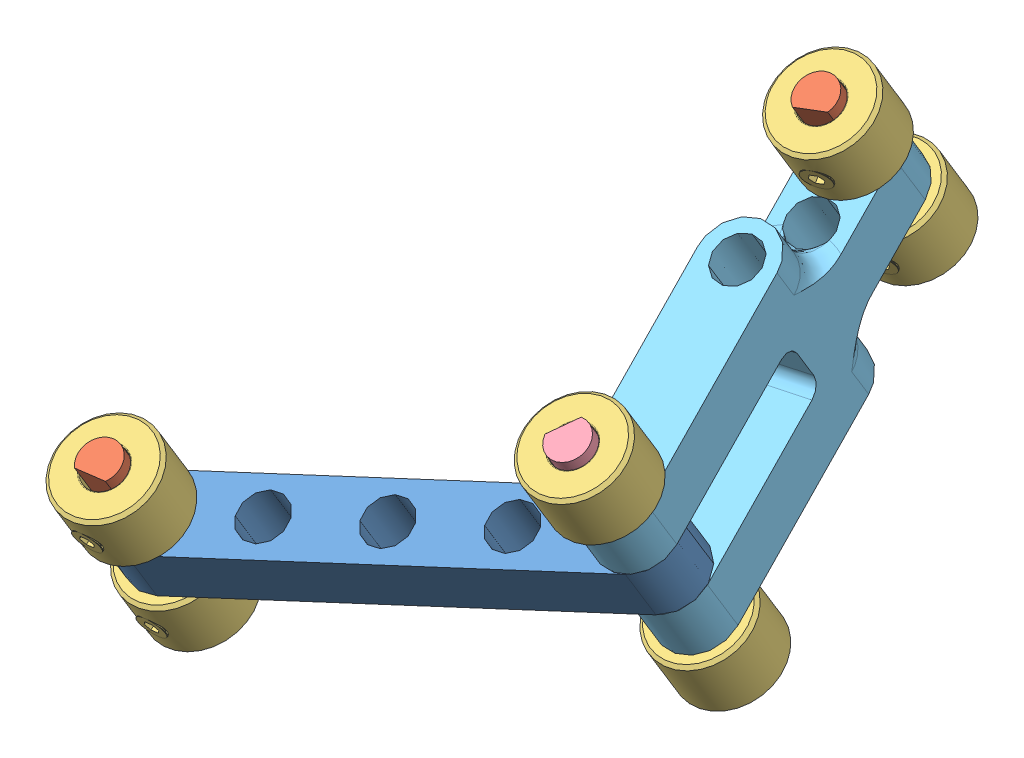
SolidWorks assembly Link Assembly, configuration Default. Lengths in mm.
Overall size (35.74 36.26 46.82).
11 component instances, 5 part files, 31 mates.
Components (placement in the parent):
- Base Link-1: Base Link [Default] at (197.5277 -2.253 -4.4836) x (0.901914 0.22428 -0.369121) z (0 0.854612 0.519267) size (35.35 5.35 4.5)
- Aluminum D Shaft-1: Aluminum D Shaft [Default] at (183.999 -5.6172 1.0532) x (0 -0.854612 -0.519267) z (-0.995127 -0.051201 0.084268) size (16 2.4 2.9)
- 6056N11_Carbon Steel Set Screw Collar-1: 6056N11_Carbon Steel Set Screw Collar [6056N11] at (183.999 -11.8131 -2.7114) x (-0.995127 -0.051201 0.084268) z (0 0.854612 0.519267) size (7 7.1 5)
- 6056N11_Carbon Steel Set Screw Collar-2: 6056N11_Carbon Steel Set Screw Collar [6056N11] at (183.999 -3.6943 2.2216) x (-0.995127 -0.051201 0.084268) z (0 0.854612 0.519267) size (7 7.1 5)
- Aluminum D Shaft-2: Aluminum D Shaft [Default] at (206.6692 13.8914 -31.0541) x (0 0.854612 0.519267) z (0.941762 0.17462 -0.28739) size (16 2.4 2.9)
- 6056N11_Carbon Steel Set Screw Collar-3: 6056N11_Carbon Steel Set Screw Collar [6056N11] at (206.6692 7.6955 -34.8188) x (-0.941762 -0.17462 0.28739) z (0 0.854612 0.519267) size (7 7.1 5)
- 6056N11_Carbon Steel Set Screw Collar-4: 6056N11_Carbon Steel Set Screw Collar [6056N11] at (206.6692 15.8143 -29.8858) x (-0.941762 -0.17462 0.28739) z (0 0.854612 0.519267) size (7 7.1 5)
- Link D Shaft-1: Link D Shaft [Default] at (211.0564 1.1112 -10.0204) x (0 -0.854612 -0.519267) z (0.552359 0.432864 -0.71241) size (25 2.4 2.9)
- 6056N11_Carbon Steel Set Screw Collar-5: 6056N11_Carbon Steel Set Screw Collar [6056N11] at (211.0564 -8.9305 -16.1218) x (0.552359 0.432864 -0.71241) z (0 0.854612 0.519267) size (7 7.1 5)
- 6056N11_Carbon Steel Set Screw Collar-6: 6056N11_Carbon Steel Set Screw Collar [6056N11] at (211.0564 6.8798 -6.5153) x (0.552359 0.432864 -0.71241) z (0 0.854612 0.519267) size (7 7.1 5)
- Upper Link-2: Upper Link [Default] at (209.3015 6.2233 -18.4339) x (-0.175488 0.511209 -0.84135) z (0 0.854612 0.519267) size (30.35 5.35 13.5)
Mates (geometry in assembly coordinates):
- Concentric30: concentric aligned: cylinder of Base Link-1 through (211.0564 3.0341 -8.852) axis (0 -0.854612 -0.519267) radius 1.675; cylinder of Upper Link-1 through (199.4791 31.9793 -36.1428) axis (0 -0.854612 -0.519267) radius 1.51
- Coincident32: coincident aligned: plane of Base Link-1 through (197.5277 -2.253 -4.4836) normal (0 0.854612 0.519267); plane of Upper Link-1 through (206.0825 22.3111 -33.2299) normal (0 0.854612 0.519267)
- Concentric52: concentric aligned: cylinder of Aluminum D Shaft-1 through (183.999 1.2197 5.2074) axis (0 -0.854612 -0.519267) radius 1.45; cylinder of 6056N11_Carbon Steel Set Screw Collar-1 through (183.999 -7.5401 -0.1151) axis (0 -0.854612 -0.519267) radius 1.5
- Parallel22: parallel aligned: plane of Aluminum D Shaft-1 through (184.0927 0.7288 6.0153) normal (0.098603 -0.516737 0.850447); plane of 6056N11_Carbon Steel Set Screw Collar-1 through (184.3441 -11.4852 1.5633) normal (0.098603 -0.516737 0.850447)
- Concentric53: concentric aligned: cylinder of Aluminum D Shaft-1 through (183.999 1.2197 5.2074) axis (0 -0.854612 -0.519267) radius 1.45; cylinder of 6056N11_Carbon Steel Set Screw Collar-2 through (183.999 0.5787 4.8179) axis (0 -0.854612 -0.519267) radius 1.5
- Parallel23: parallel aligned: plane of Aluminum D Shaft-1 through (184.0927 0.7288 6.0153) normal (0.098603 -0.516737 0.850447); plane of 6056N11_Carbon Steel Set Screw Collar-2 through (184.3441 -3.3664 6.4963) normal (0.098603 -0.516737 0.850447)
- Coincident134: coincident aligned: plane of Base Link-1 through (197.5277 -2.253 -4.4836) normal (0 0.854612 0.519267); plane of Aluminum D Shaft-2 through (206.6692 13.8914 -31.0541) normal (0 0.854612 0.519267)
- Concentric78: concentric anti-aligned: cylinder of Aluminum D Shaft-2 through (206.6692 7.0545 -35.2083) axis (0 0.854612 0.519267) radius 1.45; cylinder of 6056N11_Carbon Steel Set Screw Collar-4 through (206.6692 20.0874 -27.2894) axis (0 -0.854612 -0.519267) radius 1.5
- Concentric79: concentric anti-aligned: cylinder of Aluminum D Shaft-2 through (206.6692 7.0545 -35.2083) axis (0 0.854612 0.519267) radius 1.45; cylinder of 6056N11_Carbon Steel Set Screw Collar-3 through (206.6692 11.9685 -32.2225) axis (0 -0.854612 -0.519267) radius 1.5
- Parallel31: parallel aligned: plane of Aluminum D Shaft-2 through (206.9887 6.59 -34.4437) normal (0.336281 -0.489026 0.804841); plane of 6056N11_Carbon Steel Set Screw Collar-3 through (207.8462 8.1204 -30.7037) normal (0.336281 -0.489026 0.804841)
- Parallel32: parallel aligned: plane of Aluminum D Shaft-2 through (206.9887 6.59 -34.4437) normal (0.336281 -0.489026 0.804841); plane of 6056N11_Carbon Steel Set Screw Collar-4 through (207.8462 16.2392 -25.7707) normal (0.336281 -0.489026 0.804841)
- Coincident178: coincident anti-aligned: plane of Upper Link-1 through (206.0825 22.3111 -33.2299) normal (0 0.854612 0.519267); plane of Link D Shaft-1 through (211.0564 1.1112 -10.0204) normal (0 -0.854612 -0.519267)
- Concentric113: concentric anti-aligned: cylinder of Upper Link-1 through (199.4791 20.4421 -43.1529) axis (0 0.854612 0.519267) radius 1.51; cylinder of Link D Shaft-1 through (211.0564 11.7938 -3.5295) axis (0 -0.854612 -0.519267) radius 1.45
- Concentric114: concentric aligned: cylinder of Link D Shaft-1 through (211.0564 11.7938 -3.5295) axis (0 -0.854612 -0.519267) radius 1.45; cylinder of 6056N11_Carbon Steel Set Screw Collar-5 through (211.0564 -4.6574 -13.5254) axis (0 -0.854612 -0.519267) radius 1.5
- Parallel33: parallel aligned: plane of Link D Shaft-1 through (210.2645 12.0663 -3.978) normal (-0.833606 0.286822 -0.472053); plane of 6056N11_Carbon Steel Set Screw Collar-5 through (208.1388 -5.7901 -16.4758) normal (-0.833606 0.286822 -0.472053)
- Concentric115: concentric aligned: cylinder of Link D Shaft-1 through (211.0564 11.7938 -3.5295) axis (0 -0.854612 -0.519267) radius 1.45; cylinder of 6056N11_Carbon Steel Set Screw Collar-6 through (211.0564 11.1529 -3.919) axis (0 -0.854612 -0.519267) radius 1.5
- Parallel34: parallel aligned: plane of Link D Shaft-1 through (210.2645 12.0663 -3.978) normal (-0.833606 0.286822 -0.472053); plane of 6056N11_Carbon Steel Set Screw Collar-6 through (208.1388 10.0202 -6.8693) normal (-0.833606 0.286822 -0.472053)
- Coincident179: coincident anti-aligned: plane of Upper Link-1 through (206.0825 16.5425 -36.735) normal (0 -0.854612 -0.519267); plane of 6056N11_Carbon Steel Set Screw Collar-5 through (211.0564 -4.6574 -13.5254) normal (0 0.854612 0.519267)
- Coincident181: coincident anti-aligned: plane of Upper Link-1 through (206.0825 28.0798 -29.7249) normal (0 0.854612 0.519267); plane of 6056N11_Carbon Steel Set Screw Collar-6 through (211.0564 6.8798 -6.5153) normal (0 -0.854612 -0.519267)
- Concentric130: concentric anti-aligned: cylinder of Link D Shaft-1 through (211.0564 11.7938 -3.5295) axis (0 -0.854612 -0.519267) radius 1.45; cylinder of Upper Link-2 through (211.0564 -4.6574 -13.5254) axis (0 0.854612 0.519267) radius 1.675
- Concentric131: concentric anti-aligned: cylinder of Aluminum D Shaft-2 through (206.6692 7.0545 -35.2083) axis (0 0.854612 0.519267) radius 1.45; cylinder of Upper Link-2 through (206.6692 15.8143 -29.8858) axis (0 -0.854612 -0.519267) radius 1.675
- Concentric132: concentric anti-aligned: cylinder of Base Link-1 through (211.0564 3.0341 -8.852) axis (0 -0.854612 -0.519267) radius 1.675; cylinder of Upper Link-2 through (211.0564 -4.6574 -13.5254) axis (0 0.854612 0.519267) radius 1.675
- Coincident204: coincident anti-aligned: plane of 6056N11_Carbon Steel Set Screw Collar-5 through (211.0564 -4.6574 -13.5254) normal (0 0.854612 0.519267); plane of Upper Link-2 through (208.4241 3.0107 -26.1457) normal (0 -0.854612 -0.519267)
- Coincident205: coincident anti-aligned: plane of 6056N11_Carbon Steel Set Screw Collar-6 through (211.0564 6.8798 -6.5153) normal (0 -0.854612 -0.519267); plane of Upper Link-2 through (208.4241 14.548 -19.1356) normal (0 0.854612 0.519267)
- Coincident206: coincident anti-aligned: plane of Link D Shaft-1 through (211.0564 1.1112 -10.0204) normal (0 -0.854612 -0.519267); plane of Upper Link-2 through (209.3015 6.2233 -18.4339) normal (0 0.854612 0.519267)
- Coincident207: coincident aligned: plane of Base Link-1 through (197.5277 -2.253 -4.4836) normal (0 0.854612 0.519267); plane of Upper Link-2 through (209.3015 6.2233 -18.4339) normal (0 0.854612 0.519267)
- Parallel35: parallel aligned: plane of Aluminum D Shaft-2 through (206.9887 6.59 -34.4437) normal (0.336281 -0.489026 0.804841); plane of 6056N11_Carbon Steel Set Screw Collar-4 through (207.8462 16.2392 -25.7707) normal (0.336281 -0.489026 0.804841)
- Parallel36: parallel aligned: plane of Aluminum D Shaft-2 through (206.9887 6.59 -34.4437) normal (0.336281 -0.489026 0.804841); plane of 6056N11_Carbon Steel Set Screw Collar-3 through (207.8462 8.1204 -30.7037) normal (0.336281 -0.489026 0.804841)
- Concentric133: concentric aligned: cylinder of Base Link-1 through (183.999 -3.6943 2.2216) axis (0 -0.854612 -0.519267) radius 1.675; cylinder of Aluminum D Shaft-1 through (183.999 1.2197 5.2074) axis (0 -0.854612 -0.519267) radius 1.45
- Coincident212: coincident anti-aligned: plane of Base Link-1 through (197.5277 -2.253 -4.4836) normal (0 0.854612 0.519267); plane of Aluminum D Shaft-1 through (183.999 -5.6172 1.0532) normal (0 -0.854612 -0.519267)
- Parallel37: parallel aligned: plane of Aluminum D Shaft-1 through (184.0927 0.7288 6.0153) normal (0.098603 -0.516737 0.850447); plane of 6056N11_Carbon Steel Set Screw Collar-2 through (184.3441 -3.3664 6.4963) normal (0.098603 -0.516737 0.850447)
